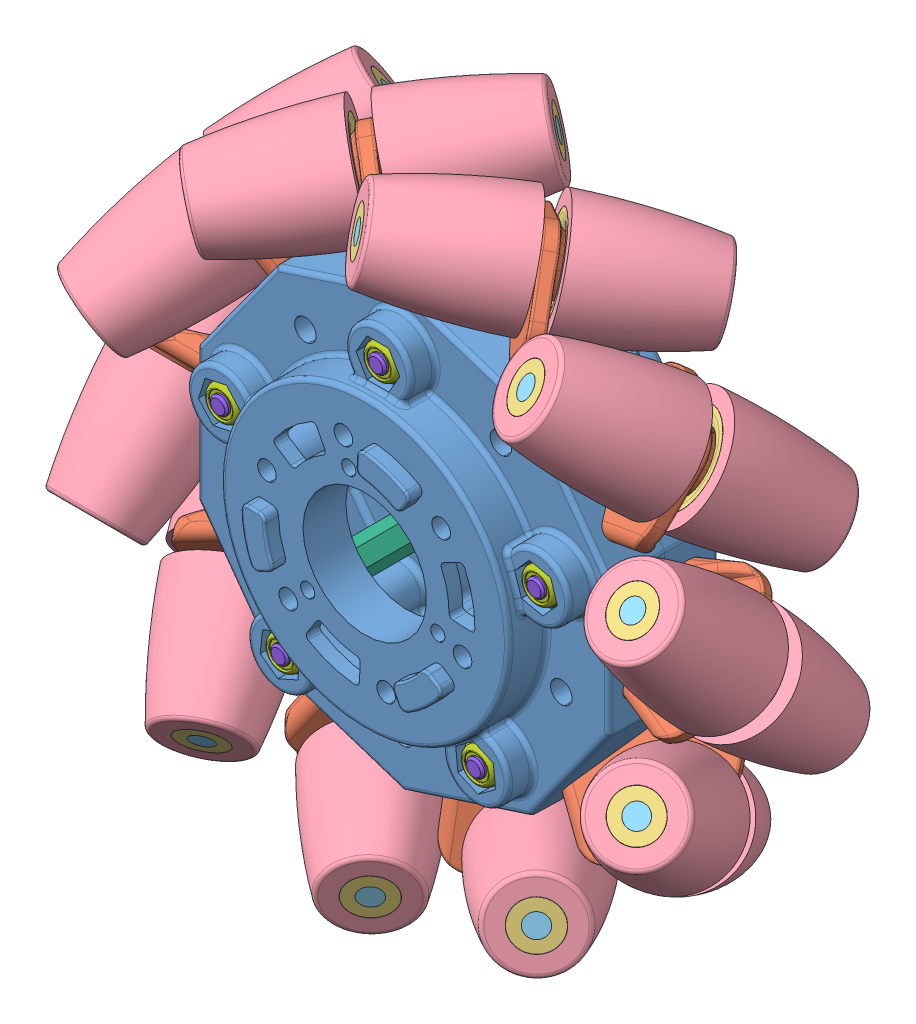
SolidWorks assembly 6_Mecanum_Wheel_Left_217-2799, configuration Default. Lengths in mm.
Overall size (160.5 167.62 65.82).
98 component instances, 9 part files, 0 mates.
Components (placement in the parent):
- 217-2799-001 Rev1-1: 217-2799-001 Rev1 [Default] at (0 0 6.35) size (95.78 100.46 28.55)
- 217-2799-001 Rev1-2: 217-2799-001 Rev1 [Default] at (0 0 -6.35) x (-0.809017 0.587785 0) z (0 0 -1) size (95.78 100.46 28.55)
- 217-2799-002 Rev1-1: 217-2799-002 Rev1 [Default] at (-41.4796 0 0) x (0 1 0) z (-1 0 0) size (26.84 25.28 30.09)
- 217-2586-003 Rev2-1: 217-2586-003 Rev2 [Default] at (-62.2568 4.0062 -4.0062) x (0.900568 0.30739 0.30739) z (-0.434715 0.636798 0.636798) size (19.46 28.57 19.46)
- 217-2586-003 Rev2-2: 217-2586-003 Rev2 [Default] at (-62.2568 -4.0062 4.0062) x (0.918161 -0.280161 -0.280161) z (-0.396207 -0.649238 -0.649238) size (19.46 28.57 19.46)
- 217-2586-004 Rev1-1: 217-2586-004 Rev1 [Default] at (-62.2568 -0.4056 0.4056) x (-0.999474 -0.02293 -0.02293) z (0.032428 -0.706735 -0.706735) size (25.9 28.58 25.9)
- 217-2586-004 Rev1-2: 217-2586-004 Rev1 [Default] at (-62.2568 0.4047 -0.4047) x (-0.563522 -0.584142 -0.584142) z (-0.826101 0.39847 0.39847) size (25.9 28.58 25.9)
- 217-2586-007 Rev1-1: 217-2586-007 Rev1 [Default] at (-62.2568 0 0) x (0 -0.707107 0.707107) z (-0.999992 0.002763 0.002763) size (61.72 5 5)
- 217-2586-008 Rev1-1: 217-2586-008 Rev1 [Default] at (4.9509 -23.2921 -0.127) x (0.978148 0.207912 0) z (0 0 -1) size (7.33 6.35 31.75)
- NUT-832-NYLOCK-1: NUT-832-NYLOCK [Default] at (0 38.5 13.6563) x (-0.5 -0.866025 0) z (-0.866025 0.5 0) size (10.2 5.86 8.12)
- SCREW-832-1250-1: SCREW-832-1250 [Default] at (0 38.5 -14.9098) x (0 0 1) z (0.371063 0.928608 0) size (33.96 7.92 7.92)
- 217-2586-007 Rev1-2: 217-2586-007 Rev1 [Default] at (-50.3668 36.5937 0) x (-0.415627 -0.572061 0.707107) z (-0.807387 0.590016 0.002763) size (61.72 5 5)
- 217-2586-007 Rev1-3: 217-2586-007 Rev1 [Default] at (-19.2384 59.2098 0) x (-0.672499 -0.218508 0.707107) z (-0.306387 0.951903 0.002763) size (61.72 5 5)
- 217-2586-007 Rev1-4: 217-2586-007 Rev1 [Default] at (19.2384 59.2098 0) x (-0.672499 0.218508 0.707107) z (0.311642 0.950196 0.002763) size (61.72 5 5)
- 217-2586-007 Rev1-5: 217-2586-007 Rev1 [Default] at (50.3668 36.5937 0) x (-0.415627 0.572061 0.707107) z (0.810635 0.585546 0.002763) size (61.72 5 5)
- 217-2586-007 Rev1-6: 217-2586-007 Rev1 [Default] at (62.2568 0 0) x (0 0.707107 0.707107) z (0.999992 -0.002763 0.002763) size (61.72 5 5)
- 217-2586-007 Rev1-7: 217-2586-007 Rev1 [Default] at (50.3668 -36.5937 0) x (0.415627 0.572061 0.707107) z (0.807387 -0.590016 0.002763) size (61.72 5 5)
- 217-2586-007 Rev1-8: 217-2586-007 Rev1 [Default] at (19.2384 -59.2098 0) x (0.672499 0.218508 0.707107) z (0.306387 -0.951903 0.002763) size (61.72 5 5)
- 217-2586-007 Rev1-9: 217-2586-007 Rev1 [Default] at (-19.2384 -59.2098 0) x (0.672499 -0.218508 0.707107) z (-0.311642 -0.950196 0.002763) size (61.72 5 5)
- 217-2586-007 Rev1-10: 217-2586-007 Rev1 [Default] at (-50.3668 -36.5937 0) x (0.415627 -0.572061 0.707107) z (-0.810635 -0.585546 0.002763) size (61.72 5 5)
- 217-2586-004 Rev1-3: 217-2586-004 Rev1 [Default] at (-50.129 36.921 -0.4047) x (-0.799249 -0.14135 -0.584142) z (-0.434115 0.807939 0.39847) size (25.9 28.58 25.9)
- 217-2586-004 Rev1-4: 217-2586-004 Rev1 [Default] at (-18.8536 59.3348 -0.4047) x (-0.72969 0.355432 -0.584142) z (0.123689 0.908803 0.39847) size (25.9 28.58 25.9)
- 217-2586-004 Rev1-5: 217-2586-004 Rev1 [Default] at (19.6233 59.0847 -0.4047) x (-0.381414 0.716451 -0.584142) z (0.634247 0.662535 0.39847) size (25.9 28.58 25.9)
- 217-2586-004 Rev1-6: 217-2586-004 Rev1 [Default] at (50.6047 36.2663 -0.4047) x (0.112549 0.80381 -0.584142) z (0.902545 0.163201 0.39847) size (25.9 28.58 25.9)
- 217-2586-004 Rev1-7: 217-2586-004 Rev1 [Default] at (62.2568 -0.4047 -0.4047) x (0.563522 0.584142 -0.584142) z (0.826101 -0.39847 0.39847) size (25.9 28.58 25.9)
- 217-2586-004 Rev1-8: 217-2586-004 Rev1 [Default] at (50.129 -36.921 -0.4047) x (0.799249 0.14135 -0.584142) z (0.434115 -0.807939 0.39847) size (25.9 28.58 25.9)
- 217-2586-004 Rev1-9: 217-2586-004 Rev1 [Default] at (18.8536 -59.3348 -0.4047) x (0.72969 -0.355432 -0.584142) z (-0.123689 -0.908803 0.39847) size (25.9 28.58 25.9)
- 217-2586-004 Rev1-10: 217-2586-004 Rev1 [Default] at (-19.6233 -59.0847 -0.4047) x (0.381414 -0.716451 -0.584142) z (-0.634247 -0.662535 0.39847) size (25.9 28.58 25.9)
- 217-2586-004 Rev1-11: 217-2586-004 Rev1 [Default] at (-50.6047 -36.2663 -0.4047) x (-0.112549 -0.80381 -0.584142) z (-0.902545 -0.163201 0.39847) size (25.9 28.58 25.9)
- 217-2586-004 Rev1-12: 217-2586-004 Rev1 [Default] at (-50.6053 36.2655 0.4056) x (-0.82207 0.568925 -0.02293) z (-0.389173 -0.590821 -0.706735) size (25.9 28.58 25.9)
- 217-2586-004 Rev1-13: 217-2586-004 Rev1 [Default] at (-19.6242 59.0844 0.4056) x (-0.330662 0.943471 -0.02293) z (-0.662124 -0.249234 -0.706735) size (25.9 28.58 25.9)
- 217-2586-004 Rev1-14: 217-2586-004 Rev1 [Default] at (18.8527 59.3351 0.4056) x (0.287047 0.957642 -0.02293) z (-0.682166 0.187552 -0.706735) size (25.9 28.58 25.9)
- 217-2586-004 Rev1-15: 217-2586-004 Rev1 [Default] at (50.1284 36.9218 0.4056) x (0.795114 0.606027 -0.02293) z (-0.441643 0.5527 -0.706735) size (25.9 28.58 25.9)
- 217-2586-004 Rev1-16: 217-2586-004 Rev1 [Default] at (62.2568 0.4056 0.4056) x (0.999474 0.02293 -0.02293) z (-0.032428 0.706735 -0.706735) size (25.9 28.58 25.9)
- 217-2586-004 Rev1-17: 217-2586-004 Rev1 [Default] at (50.6053 -36.2655 0.4056) x (0.82207 -0.568925 -0.02293) z (0.389173 0.590821 -0.706735) size (25.9 28.58 25.9)
- 217-2586-004 Rev1-18: 217-2586-004 Rev1 [Default] at (19.6242 -59.0844 0.4056) x (0.330662 -0.943471 -0.02293) z (0.662124 0.249234 -0.706735) size (25.9 28.58 25.9)
- 217-2586-004 Rev1-19: 217-2586-004 Rev1 [Default] at (-18.8527 -59.3351 0.4056) x (-0.287047 -0.957642 -0.02293) z (0.682166 -0.187552 -0.706735) size (25.9 28.58 25.9)
- 217-2586-004 Rev1-20: 217-2586-004 Rev1 [Default] at (-50.1284 -36.9218 0.4056) x (-0.795114 -0.606027 -0.02293) z (0.441643 -0.5527 -0.706735) size (25.9 28.58 25.9)
- 217-2586-003 Rev2-3: 217-2586-003 Rev2 [Default] at (-52.7216 33.3525 4.0062) x (0.578133 -0.766336 -0.280161) z (-0.702151 -0.29236 -0.649238) size (19.46 28.57 19.46)
- 217-2586-003 Rev2-4: 217-2586-003 Rev2 [Default] at (-23.0486 57.9718 4.0062) x (0.017279 -0.959798 -0.280161) z (-0.739897 0.17619 -0.649238) size (19.46 28.57 19.46)
- 217-2586-003 Rev2-5: 217-2586-003 Rev2 [Default] at (15.4283 60.4478 4.0062) x (-0.550176 -0.786649 -0.280161) z (-0.495027 0.577441 -0.649238) size (19.46 28.57 19.46)
- 217-2586-003 Rev2-6: 217-2586-003 Rev2 [Default] at (48.012 39.8348 4.0062) x (-0.907482 -0.313027 -0.280161) z (-0.061074 0.758129 -0.649238) size (19.46 28.57 19.46)
- 217-2586-003 Rev2-7: 217-2586-003 Rev2 [Default] at (62.2568 4.0062 4.0062) x (-0.918161 0.280161 -0.280161) z (0.396207 0.649238 -0.649238) size (19.46 28.57 19.46)
- 217-2586-003 Rev2-8: 217-2586-003 Rev2 [Default] at (52.7216 -33.3525 4.0062) x (-0.578133 0.766336 -0.280161) z (0.702151 0.29236 -0.649238) size (19.46 28.57 19.46)
- 217-2586-003 Rev2-9: 217-2586-003 Rev2 [Default] at (23.0486 -57.9718 4.0062) x (-0.017279 0.959798 -0.280161) z (0.739897 -0.17619 -0.649238) size (19.46 28.57 19.46)
- 217-2586-003 Rev2-10: 217-2586-003 Rev2 [Default] at (-15.4283 -60.4478 4.0062) x (0.550176 0.786649 -0.280161) z (0.495027 -0.577441 -0.649238) size (19.46 28.57 19.46)
- 217-2586-003 Rev2-11: 217-2586-003 Rev2 [Default] at (-48.012 -39.8348 4.0062) x (0.907482 0.313027 -0.280161) z (0.061074 -0.758129 -0.649238) size (19.46 28.57 19.46)
- 217-2586-003 Rev2-12: 217-2586-003 Rev2 [Default] at (-48.012 39.8348 -4.0062) x (0.909254 -0.280657 0.30739) z (0.022609 0.770699 0.636798) size (19.46 28.57 19.46)
- 217-2586-003 Rev2-13: 217-2586-003 Rev2 [Default] at (-15.4283 60.4478 -4.0062) x (0.570636 -0.761502 0.30739) z (0.471296 0.61022 0.636798) size (19.46 28.57 19.46)
- 217-2586-003 Rev2-14: 217-2586-003 Rev2 [Default] at (23.0486 57.9718 -4.0062) x (0.014054 -0.95148 0.30739) z (0.739965 0.216657 0.636798) size (19.46 28.57 19.46)
- 217-2586-003 Rev2-15: 217-2586-003 Rev2 [Default] at (52.7216 33.3525 -4.0062) x (-0.547896 -0.778024 0.30739) z (0.725992 -0.259661 0.636798) size (19.46 28.57 19.46)
- 217-2586-003 Rev2-16: 217-2586-003 Rev2 [Default] at (62.2568 -4.0062 -4.0062) x (-0.900568 -0.30739 0.30739) z (0.434715 -0.636798 0.636798) size (19.46 28.57 19.46)
- 217-2586-003 Rev2-17: 217-2586-003 Rev2 [Default] at (48.012 -39.8348 -4.0062) x (-0.909254 0.280657 0.30739) z (-0.022609 -0.770699 0.636798) size (19.46 28.57 19.46)
- 217-2586-003 Rev2-18: 217-2586-003 Rev2 [Default] at (15.4283 -60.4478 -4.0062) x (-0.570636 0.761502 0.30739) z (-0.471296 -0.61022 0.636798) size (19.46 28.57 19.46)
- 217-2586-003 Rev2-19: 217-2586-003 Rev2 [Default] at (-23.0486 -57.9718 -4.0062) x (-0.014054 0.95148 0.30739) z (-0.739965 -0.216657 0.636798) size (19.46 28.57 19.46)
- 217-2586-003 Rev2-20: 217-2586-003 Rev2 [Default] at (-52.7216 -33.3525 -4.0062) x (0.547896 0.778024 0.30739) z (-0.725992 0.259661 0.636798) size (19.46 28.57 19.46)
- 217-2799-002 Rev1-2: 217-2799-002 Rev1 [Default] at (-33.5577 24.3811 0) x (0.587785 0.809017 0) z (-0.809017 0.587785 0) size (26.84 25.28 30.09)
- 217-2799-002 Rev1-3: 217-2799-002 Rev1 [Default] at (-12.8179 39.4495 0) x (0.951057 0.309017 0) z (-0.309017 0.951057 0) size (26.84 25.28 30.09)
- 217-2799-002 Rev1-4: 217-2799-002 Rev1 [Default] at (12.8179 39.4495 0) x (0.951057 -0.309017 0) z (0.309017 0.951057 0) size (26.84 25.28 30.09)
- 217-2799-002 Rev1-5: 217-2799-002 Rev1 [Default] at (33.5577 24.3811 0) x (0.587785 -0.809017 0) z (0.809017 0.587785 0) size (26.84 25.28 30.09)
- 217-2799-002 Rev1-6: 217-2799-002 Rev1 [Default] at (41.4796 0 0) x (0 -1 0) z (1 0 0) size (26.84 25.28 30.09)
- 217-2799-002 Rev1-7: 217-2799-002 Rev1 [Default] at (33.5577 -24.3811 0) x (-0.587785 -0.809017 0) z (0.809017 -0.587785 0) size (26.84 25.28 30.09)
- 217-2799-002 Rev1-8: 217-2799-002 Rev1 [Default] at (12.8179 -39.4495 0) x (-0.951057 -0.309017 0) z (0.309017 -0.951057 0) size (26.84 25.28 30.09)
- 217-2799-002 Rev1-9: 217-2799-002 Rev1 [Default] at (-12.8179 -39.4495 0) x (-0.951057 0.309017 0) z (-0.309017 -0.951057 0) size (26.84 25.28 30.09)
- 217-2799-002 Rev1-10: 217-2799-002 Rev1 [Default] at (-33.5577 -24.3811 0) x (-0.587785 0.809017 0) z (-0.809017 -0.587785 0) size (26.84 25.28 30.09)
- 217-2586-008 Rev1-2: 217-2586-008 Rev1 [Default] at (-17.6961 -15.9337 -0.127) x (0.669131 -0.743145 0) z (0 0 -1) size (7.33 6.35 31.75)
- 217-2586-008 Rev1-3: 217-2586-008 Rev1 [Default] at (-22.647 7.3585 -0.127) x (-0.309017 -0.951057 0) z (0 0 -1) size (7.33 6.35 31.75)
- 217-2586-008 Rev1-4: 217-2586-008 Rev1 [Default] at (-4.9509 23.2921 -0.127) x (-0.978148 -0.207912 0) z (0 0 -1) size (7.33 6.35 31.75)
- 217-2586-008 Rev1-5: 217-2586-008 Rev1 [Default] at (17.6961 15.9337 -0.127) x (-0.669131 0.743145 0) z (0 0 -1) size (7.33 6.35 31.75)
- 217-2586-008 Rev1-6: 217-2586-008 Rev1 [Default] at (22.647 -7.3585 -0.127) x (0.309017 0.951057 0) z (0 0 -1) size (7.33 6.35 31.75)
- SCREW-832-1250-2: SCREW-832-1250 [Default] at (-36.6157 11.8972 -14.9098) x (0 0 1) z (-0.768494 0.639858 0) size (33.96 7.92 7.92)
- SCREW-832-1250-3: SCREW-832-1250 [Default] at (-22.6297 -31.1472 -14.9098) x (0 0 1) z (-0.846018 -0.533154 0) size (33.96 7.92 7.92)
- SCREW-832-1250-4: SCREW-832-1250 [Default] at (22.6297 -31.1472 -14.9098) x (0 0 1) z (0.245625 -0.969365 0) size (33.96 7.92 7.92)
- SCREW-832-1250-5: SCREW-832-1250 [Default] at (36.6157 11.8972 -14.9098) x (0 0 1) z (0.997823 -0.065947 0) size (33.96 7.92 7.92)
- NUT-832-NYLOCK-2: NUT-832-NYLOCK [Default] at (-36.6157 11.8972 13.6563) x (0.669131 -0.743145 0) z (-0.743145 -0.669131 0) size (10.2 5.86 8.12)
- NUT-832-NYLOCK-3: NUT-832-NYLOCK [Default] at (-22.6297 -31.1472 13.6563) x (0.913545 0.406737 0) z (0.406737 -0.913545 0) size (10.2 5.86 8.12)
- NUT-832-NYLOCK-4: NUT-832-NYLOCK [Default] at (22.6297 -31.1472 13.6563) x (-0.104528 0.994522 0) z (0.994522 0.104528 0) size (10.2 5.86 8.12)
- NUT-832-NYLOCK-5: NUT-832-NYLOCK [Default] at (36.6157 11.8972 13.6563) x (-0.978148 0.207912 0) z (0.207912 0.978148 0) size (10.2 5.86 8.12)
- 217-2586-005 Rev2-1: 217-2586-005 Rev2 [Default] at (-62.2568 -6.3286 6.3286) x (0 0.707107 -0.707107) z (0.707107 0.5 0.5) size (8.5 8 8)
- 217-2586-005 Rev2-2: 217-2586-005 Rev2 [Default] at (-62.2568 6.3286 -6.3286) x (0 0.707107 -0.707107) z (0.707107 0.5 0.5) size (8.5 8 8)
- 217-2586-005 Rev2-3: 217-2586-005 Rev2 [Default] at (-46.647 41.7136 -6.3286) x (0.415627 0.572061 -0.707107) z (0.865954 -0.011118 0.5) size (8.5 8 8)
- 217-2586-005 Rev2-4: 217-2586-005 Rev2 [Default] at (-13.2196 61.1654 -6.3286) x (0.672499 0.218508 -0.707107) z (0.694036 -0.51799 0.5) size (8.5 8 8)
- 217-2586-005 Rev2-5: 217-2586-005 Rev2 [Default] at (25.2573 57.2541 -6.3286) x (0.672499 -0.218508 -0.707107) z (0.25702 -0.827007 0.5) size (8.5 8 8)
- 217-2586-005 Rev2-6: 217-2586-005 Rev2 [Default] at (54.0867 31.4737 -6.3286) x (0.415627 -0.572061 -0.707107) z (-0.278169 -0.820135 0.5) size (8.5 8 8)
- 217-2586-005 Rev2-7: 217-2586-005 Rev2 [Default] at (62.2568 -6.3286 -6.3286) x (0 -0.707107 -0.707107) z (-0.707107 -0.5 0.5) size (8.5 8 8)
- 217-2586-005 Rev2-8: 217-2586-005 Rev2 [Default] at (46.647 -41.7136 -6.3286) x (-0.415627 -0.572061 -0.707107) z (-0.865954 0.011118 0.5) size (8.5 8 8)
- 217-2586-005 Rev2-9: 217-2586-005 Rev2 [Default] at (13.2196 -61.1654 -6.3286) x (-0.672499 -0.218508 -0.707107) z (-0.694036 0.51799 0.5) size (8.5 8 8)
- 217-2586-005 Rev2-10: 217-2586-005 Rev2 [Default] at (-25.2573 -57.2541 -6.3286) x (-0.672499 0.218508 -0.707107) z (-0.25702 0.827007 0.5) size (8.5 8 8)
- 217-2586-005 Rev2-11: 217-2586-005 Rev2 [Default] at (-54.0867 -31.4737 -6.3286) x (-0.415627 0.572061 -0.707107) z (0.278169 0.820135 0.5) size (8.5 8 8)
- 217-2586-005 Rev2-12: 217-2586-005 Rev2 [Default] at (-54.0867 31.4737 6.3286) x (0.415627 0.572061 -0.707107) z (0.865954 -0.011118 0.5) size (8.5 8 8)
- 217-2586-005 Rev2-13: 217-2586-005 Rev2 [Default] at (-25.2573 57.2541 6.3286) x (0.672499 0.218508 -0.707107) z (0.694036 -0.51799 0.5) size (8.5 8 8)
- 217-2586-005 Rev2-14: 217-2586-005 Rev2 [Default] at (13.2196 61.1654 6.3286) x (0.672499 -0.218508 -0.707107) z (0.25702 -0.827007 0.5) size (8.5 8 8)
- 217-2586-005 Rev2-15: 217-2586-005 Rev2 [Default] at (46.647 41.7136 6.3286) x (0.415627 -0.572061 -0.707107) z (-0.278169 -0.820135 0.5) size (8.5 8 8)
- 217-2586-005 Rev2-16: 217-2586-005 Rev2 [Default] at (62.2568 6.3286 6.3286) x (0 -0.707107 -0.707107) z (-0.707107 -0.5 0.5) size (8.5 8 8)
- 217-2586-005 Rev2-17: 217-2586-005 Rev2 [Default] at (54.0867 -31.4737 6.3286) x (-0.415627 -0.572061 -0.707107) z (-0.865954 0.011118 0.5) size (8.5 8 8)
- 217-2586-005 Rev2-18: 217-2586-005 Rev2 [Default] at (25.2573 -57.2541 6.3286) x (-0.672499 -0.218508 -0.707107) z (-0.694036 0.51799 0.5) size (8.5 8 8)
- 217-2586-005 Rev2-19: 217-2586-005 Rev2 [Default] at (-13.2196 -61.1654 6.3286) x (-0.672499 0.218508 -0.707107) z (-0.25702 0.827007 0.5) size (8.5 8 8)
- 217-2586-005 Rev2-20: 217-2586-005 Rev2 [Default] at (-46.647 -41.7136 6.3286) x (-0.415627 0.572061 -0.707107) z (0.278169 0.820135 0.5) size (8.5 8 8)
